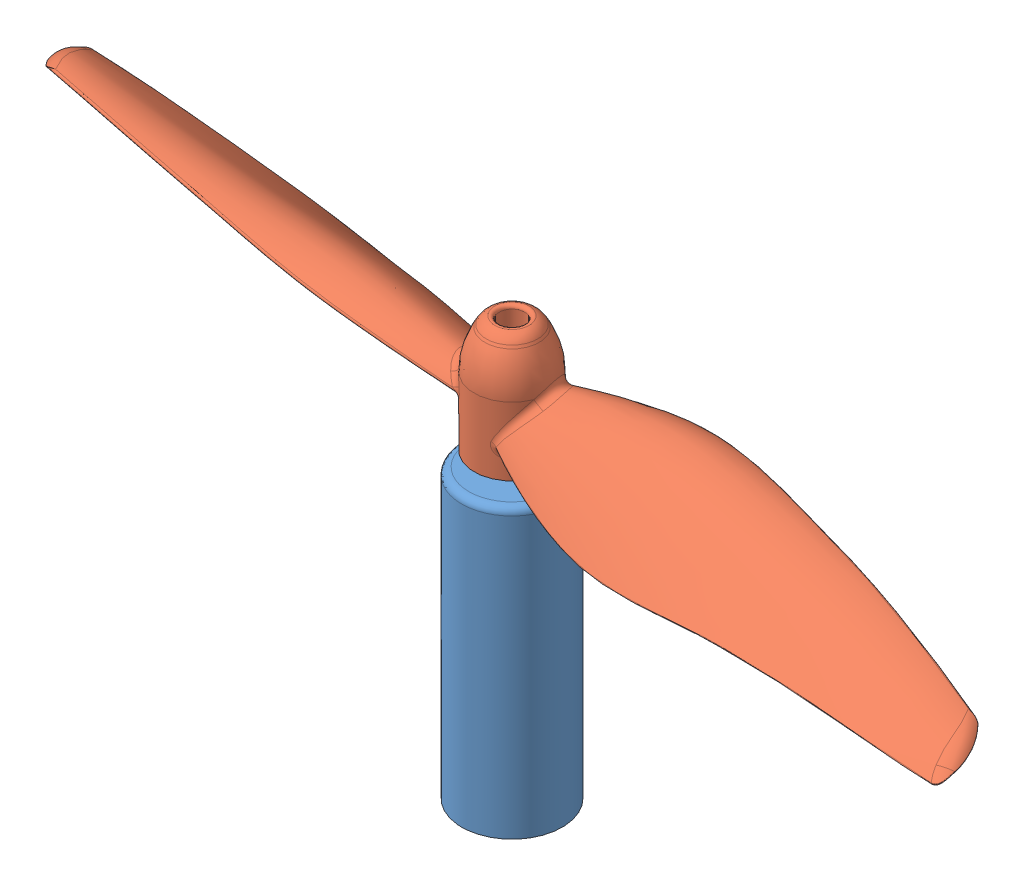
SolidWorks assembly motor assem, configuration Default. Lengths in mm.
Overall size (76.32 29.13 18.6).
2 component instances, 2 part files, 2 mates.
Components (placement in the parent):
- 615 motor-1: 615 motor [Default] at (8.211 -8.4805 -5.3652) size (7 25 7)
- 75mm Press-Fit Prop-1: 75mm Press-Fit Prop [Default] at (8.211 13.0857 -5.3652) x (0.992135 0 0.125176) z (-0.125176 0 0.992135) size (75.76 8.13 9.19)
Mates (geometry in assembly coordinates):
- Concentric1: concentric: circle of 615 motor-1; circle of 75mm Press-Fit Prop-1
- Coincident1: coincident anti-aligned: plane of 615 motor-1 through (8.211 12.5195 -5.3652) normal (0 1 0); plane of 75mm Press-Fit Prop-1 through (8.211 12.5195 -5.3652) normal (0 -1 0)
